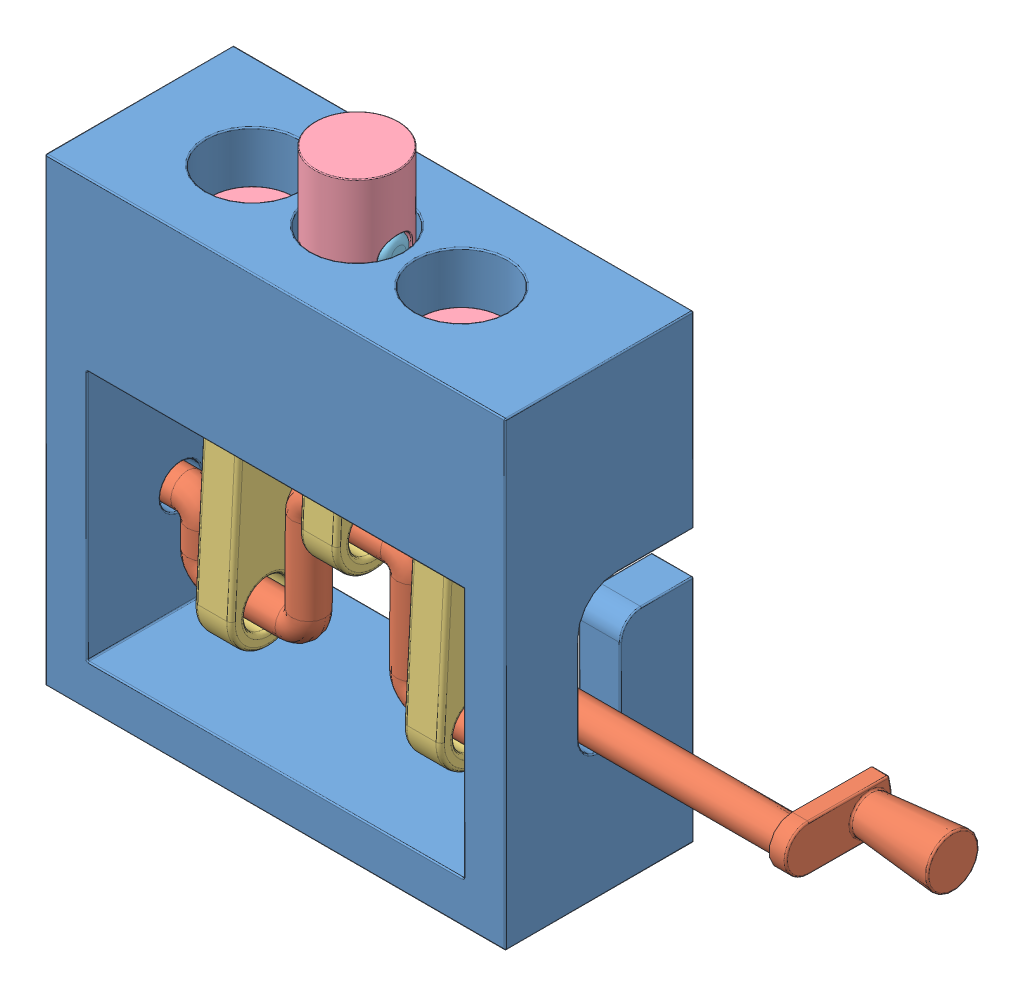
SolidWorks assembly TP-ASSY, configuration Default. Lengths in mm.
Overall size (228.6 160.65 57.15).
11 component instances, 5 part files, 20 mates.
Components (placement in the parent):
- TP-BLOCK BODY-1: TP-BLOCK BODY [Default] at (-56.5839 -63.0284 -13.7365) size (139.7 139.7 57.15)
- TP-CAMSHAFT-1: TP-CAMSHAFT [Default] at (19.4955 -18.5784 -13.7365) x (1 0 0) z (0 0.00536 0.999986) size (220.98 45.72 33.29)
- TP-CONNECTING ARM-1: TP-CONNECTING ARM [Default] at (-22.9289 -36.3582 -13.6413) x (1 0 0) z (0 0.001251 0.999999) size (11.93 95 22.86)
- TP-PISTON HEAD-1: TP-PISTON HEAD [Default] at (-22.2939 36.6668 -13.7365) size (25.71 31.88 25.4)
- TP-WRIST PIN-1: TP-WRIST PIN [Default] at (-22.2939 39.8418 -13.7365) x (1 0 0) z (0 0.698889 -0.715231) size (25.4 9.4 9.4)
- TP-CONNECTING ARM-2: TP-CONNECTING ARM [Default] at (8.8211 -0.7987 -13.8318) x (1 0 0) z (0 -0.001251 0.999999) size (11.93 95 22.86)
- TP-CONNECTING ARM-3: TP-CONNECTING ARM [Default] at (40.5711 -36.3582 -13.6413) x (1 0 0) z (0 0.001251 0.999999) size (11.93 95 22.86)
- TP-WRIST PIN-2: TP-WRIST PIN [Default] at (9.4561 75.4013 -13.7365) x (1 0 0) z (0 0.698889 -0.715231) size (25.4 9.4 9.4)
- TP-WRIST PIN-3: TP-WRIST PIN [Default] at (41.2061 39.8418 -13.7365) x (1 0 0) z (0 0.698889 -0.715231) size (25.4 9.4 9.4)
- TP-PISTON HEAD-2: TP-PISTON HEAD [Default] at (9.4561 72.2263 -13.7365) size (25.71 31.88 25.4)
- TP-PISTON HEAD-3: TP-PISTON HEAD [Default] at (41.2061 36.6668 -13.7365) size (25.71 31.88 25.4)
Mates (geometry in assembly coordinates):
- Concentric1: concentric aligned: cylinder of TP-CONNECTING ARM-1 through (-17.2139 39.8418 -13.7365) axis (-1 0 0) radius 5.08; cylinder of TP-WRIST PIN-1 through (-9.5939 39.8418 -13.7365) axis (-1 0 0) radius 4.699
- Concentric2: concentric anti-aligned: cylinder of TP-PISTON HEAD-1 through (-34.9939 39.8418 -13.7365) axis (1 0 0) radius 5.08; cylinder of TP-WRIST PIN-1 through (-9.5939 39.8418 -13.7365) axis (-1 0 0) radius 4.699
- Concentric3: concentric anti-aligned: cylinder of TP-BLOCK BODY-1 through (-22.2939 -12.2284 -13.7365) axis (0 1 0) radius 13.97; circle of TP-PISTON HEAD-1
- Concentric4: concentric aligned: cylinder of TP-BLOCK BODY-1 through (-48.9639 -18.5784 -13.7365) axis (1 0 0) radius 6.35; cylinder of TP-CAMSHAFT-1 through (63.4311 -18.5784 -13.7365) axis (1 0 0) radius 5.08
- Concentric5: concentric anti-aligned: cylinder of TP-CAMSHAFT-1 through (-31.8189 -36.3582 -13.6413) axis (1 0 0) radius 5.08; cylinder of TP-CONNECTING ARM-1 through (-17.2139 -36.3582 -13.6413) axis (-1 0 0) radius 6.985
- Coincident1: coincident anti-aligned: plane of TP-CONNECTING ARM-1 through (-28.6439 39.8418 -13.7365) normal (-1 0 0); plane of TP-PISTON HEAD-1 through (-28.6439 39.8418 -13.7365) normal (1 0 0)
- Tangent1: tangent aligned: cylinder of TP-PISTON HEAD-1 through (-22.2939 62.0668 -13.7365) axis (0 -1 0) radius 12.7; plane of TP-WRIST PIN-1 through (-9.5939 39.8418 -13.7365) normal (1 0 0)
- Coincident2: coincident anti-aligned: plane of TP-BLOCK BODY-1 through (-48.9639 -18.5784 -13.7365) normal (1 0 0); plane of TP-CAMSHAFT-1 through (-48.9639 -18.5784 -13.7365) normal (-1 0 0)
- Concentric6: concentric anti-aligned: cylinder of TP-BLOCK BODY-1 through (9.4561 -12.2284 -13.7365) axis (0 1 0) radius 13.97; cylinder of TP-PISTON HEAD-2 through (9.4561 97.6263 -13.7365) axis (0 -1 0) radius 12.7
- Concentric7: concentric anti-aligned: cylinder of TP-BLOCK BODY-1 through (41.2061 -12.2284 -13.7365) axis (0 1 0) radius 13.97; cylinder of TP-PISTON HEAD-3 through (41.2061 62.0668 -13.7365) axis (0 -1 0) radius 12.7
- Coincident3: coincident anti-aligned: plane of TP-CONNECTING ARM-2 through (3.1061 75.4013 -13.7365) normal (-1 0 0); plane of TP-PISTON HEAD-2 through (3.1061 75.4013 -13.7365) normal (1 0 0)
- Coincident4: coincident anti-aligned: plane of TP-CONNECTING ARM-3 through (34.8561 39.8418 -13.7365) normal (-1 0 0); plane of TP-PISTON HEAD-3 through (34.8561 39.8418 -13.7365) normal (1 0 0)
- Concentric8: concentric anti-aligned: cylinder of TP-CONNECTING ARM-3 through (46.2861 39.8418 -13.7365) axis (-1 0 0) radius 5.08; cylinder of TP-PISTON HEAD-3 through (28.5061 39.8418 -13.7365) axis (1 0 0) radius 5.08
- Concentric9: concentric anti-aligned: cylinder of TP-CONNECTING ARM-2 through (14.5361 75.4013 -13.7365) axis (-1 0 0) radius 5.08; cylinder of TP-PISTON HEAD-2 through (-3.2439 75.4013 -13.7365) axis (1 0 0) radius 5.08
- Concentric10: concentric aligned: cylinder of TP-CONNECTING ARM-3 through (46.2861 39.8418 -13.7365) axis (-1 0 0) radius 5.08; cylinder of TP-WRIST PIN-3 through (53.9061 39.8418 -13.7365) axis (-1 0 0) radius 4.699
- Concentric11: concentric aligned: cylinder of TP-CONNECTING ARM-2 through (14.5361 75.4013 -13.7365) axis (-1 0 0) radius 5.08; cylinder of TP-WRIST PIN-2 through (22.1561 75.4013 -13.7365) axis (-1 0 0) radius 4.699
- Tangent2: tangent aligned: plane of TP-WRIST PIN-2 through (22.1561 75.4013 -13.7365) normal (1 0 0); cylinder of TP-PISTON HEAD-2 through (9.4561 97.6263 -13.7365) axis (0 -1 0) radius 12.7
- Tangent3: tangent aligned: plane of TP-WRIST PIN-3 through (53.9061 39.8418 -13.7365) normal (1 0 0); cylinder of TP-PISTON HEAD-3 through (41.2061 62.0668 -13.7365) axis (0 -1 0) radius 12.7
- Concentric12: concentric anti-aligned: cylinder of TP-CAMSHAFT-1 through (31.6811 -36.3582 -13.6413) axis (1 0 0) radius 5.08; cylinder of TP-CONNECTING ARM-3 through (46.2861 -36.3582 -13.6413) axis (-1 0 0) radius 6.985
- Concentric13: concentric anti-aligned: cylinder of TP-CAMSHAFT-1 through (-0.0689 -0.7987 -13.8318) axis (1 0 0) radius 5.08; cylinder of TP-CONNECTING ARM-2 through (14.5361 -0.7987 -13.8318) axis (-1 0 0) radius 6.985
